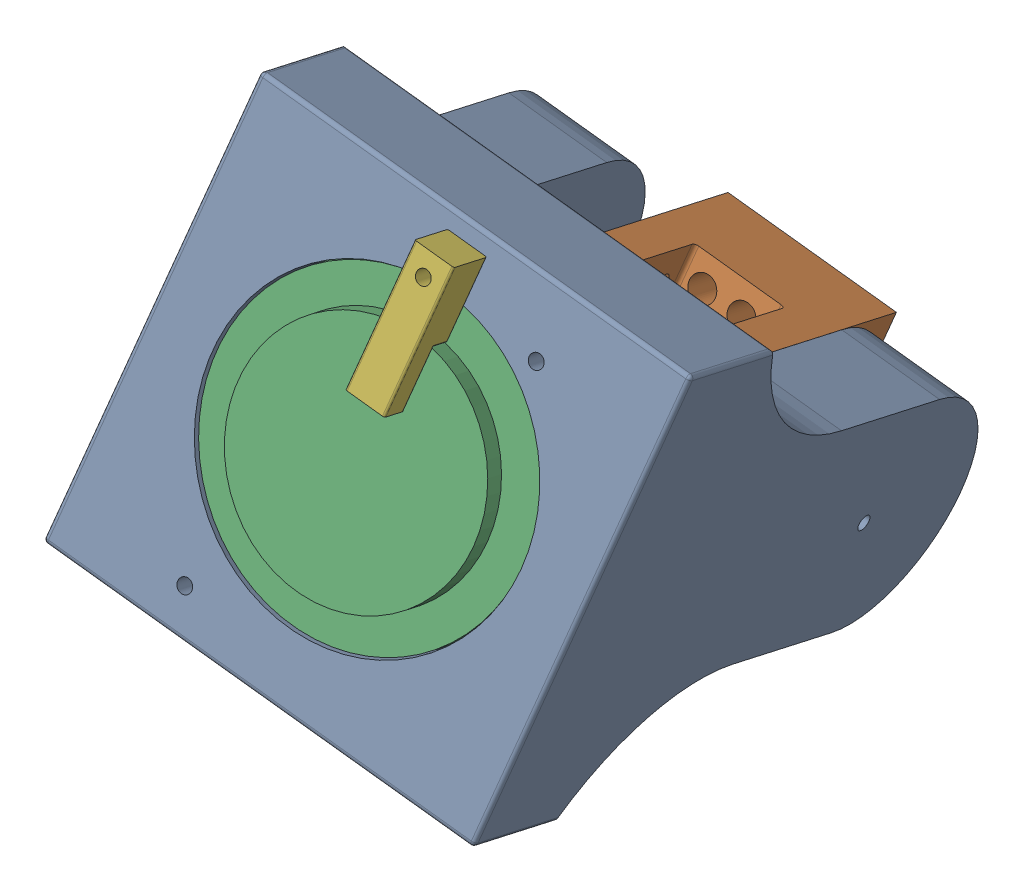
SolidWorks assembly Final_Shaker_Assembly, configuration Default. Lengths in mm.
Overall size (149.34 171.79 178.29).
7 component instances, 7 part files, 20 mates.
Components (placement in the parent):
- Final_Platform-1: Final_Platform [Default] at (-6.0583 19.4305 92.5028) x (0.96976 -0.223218 -0.098687) z (0.172494 0.340802 0.924175) size (110 110 137.25)
- Final_ServoMount-1: Final_ServoMount [Default] at (-38.0465 2.6786 -8.6405) x (0.172659 0.913251 -0.368999) z (0.96976 -0.223218 -0.098687) size (65 52.78 43)
- Chamber_Outline-1: Chamber_Outline [Default] at (-5.3684 20.7937 96.1995) x (0.981445 -0.139228 -0.13184) z (0.08374 0.929769 -0.358494) size (78 14 78)
- Final_ServoArm-1: Final_ServoArm [Default] at (-52.7711 -8.6854 1.06) x (0.171035 0.333108 0.927247) z (-0.174104 -0.916086 0.361213) size (34 7 15)
- Final_servoMotor-2: Final_servoMotor [Default] at (-27.0663 -13.0037 8.6752) x (0.172659 0.913251 -0.368999) z (-0.96976 0.223218 0.098687) size (54.5 20 47.4)
- Clamp-1: Clamp [Default] at (0.5019 51.2718 84.9467) x (-0.172659 -0.913251 0.368999) z (0.172494 0.340802 0.924175) size (35 10 12)
- Small_Clamp-4: Small_Clamp [Default] at (-7.0135 37.6602 119.946) x (-0.901611 -0.323204 0.287468) z (-0.172494 -0.340802 -0.924175) (suppressed, hidden)
Mates (geometry in assembly coordinates):
- Parallel3: parallel aligned: plane of Final_Platform-1 through (-55.0737 71.7123 49.9103) normal (0.172659 0.913251 -0.368999); plane of Final_ServoMount-1 through (-24.8459 10.8002 1.3765) normal (0.172659 0.913251 -0.368999)
- Parallel4: parallel aligned: plane of Final_ServoMount-1 through (7.7835 4.6735 1.481) normal (0.172494 0.340802 0.924175); plane of Servomotor- Shadi Approved-2 through (-27.0663 -13.0037 8.6752) normal (0.172494 0.340802 0.924175)
- Concentric14: concentric aligned: circle of Servomotor- Shadi Approved-2; circle of Servo Mount-1
- Concentric15: concentric aligned: circle of Servo Mount-1; circle of Servomotor- Shadi Approved-2
- Coincident65: coincident anti-aligned: plane of Final_ServoMount-1 through (-35.5795 7.5529 4.5774) normal (-0.96976 0.223218 0.098687); plane of Servomotor- Shadi Approved-2 through (-39.2017 0.8253 -15.8003) normal (0.96976 -0.223218 -0.098687)
- ProfileCenter36: profile center aligned: circle of Small_Clamp-1; circle of Platform_Shaker_COPYNEW_ShadiApproved_Smaller-1
- ProfileCenter38: profile center anti-aligned: plane of Chamber_Outline-1 through (-7.7833 16.0225 83.261) normal (-0.172494 -0.340802 -0.924175); plane of Final_Platform-1 through (-7.7833 16.0225 83.261) normal (0.172494 0.340802 0.924175)
- ProfileCenter39: profile center: circle of Clamp_Shaker_v2-1; circle of Platform_Shaker_COPYNEW_ShadiApproved_Smaller-1
- Parallel6: parallel aligned: plane of Final_Platform-1 through (-55.0737 71.7123 49.9103) normal (0.172659 0.913251 -0.368999); plane of Clamp-1 through (-0.1179 70.7554 85.4518) normal (0.172659 0.913251 -0.368999)
- Parallel7: parallel: plane of Final_ServoMount-1 through (-10.104 -67.8554 -10.2413) normal (-0.172659 -0.913251 0.368999); plane of BA2s5 Cad to use-1 through (38.3799 40.8829 29.5759) normal (0 -1 0)
- Concentric23: concentric anti-aligned: circle of BA2s5 Cad to use-1; circle of Second Platform Thorr Labs-1
- Parallel8: parallel: plane of BA2s5 Cad to use-1 through (38.3799 40.8829 29.5759) normal (-1 0 0); plane of Second Platform Thorr Labs-1
- Concentric24: concentric aligned: circle of Platform_Shaker_COPYNEW_ShadiApproved_Smaller-1; circle of Small_Clamp-3
- Concentric26: concentric aligned: circle of Servo Arm to Use-1; circle of Servomotor- Shadi Approved-2
- Coincident76: coincident anti-aligned: plane of Servo Arm to Use-1 through (-52.7711 -8.6854 1.06) normal (0.96976 -0.223218 -0.098687); plane of Servomotor- Shadi Approved-2 through (-59.6759 -39.491 2.8883) normal (-0.96976 0.223218 0.098687)
- Coincident78: coincident anti-aligned: plane of Final_Platform-1 through (-54.8905 2.298 26.3215) normal (0.96976 -0.223218 -0.098687); plane of Final_ServoArm-1 through (-59.5595 -7.1229 1.7508) normal (-0.96976 0.223218 0.098687)
- Parallel10: parallel aligned: plane of Final_Platform-1 through (-74.0662 -28.7454 90.5003) normal (-0.96976 0.223218 0.098687); plane of BA2s5 Cad to use-2 through (44.7332 40.8406 39.3192) normal (-1 0 0)
- Concentric27: concentric aligned: circle of Platform_Shaker_COPYNEW_ShadiApproved_Smaller-1; circle of Servo Arm to Use-1
- ProfileCenter40: profile center aligned: circle of Small_Clamp-4; circle of Platform_Shaker_COPYNEW_ShadiApproved_Smaller-1
- Concentric28: concentric anti-aligned: circle of Platform_Shaker_COPYNEW_ShadiApproved_Smaller-1; circle of Servo Arm to Use-1
